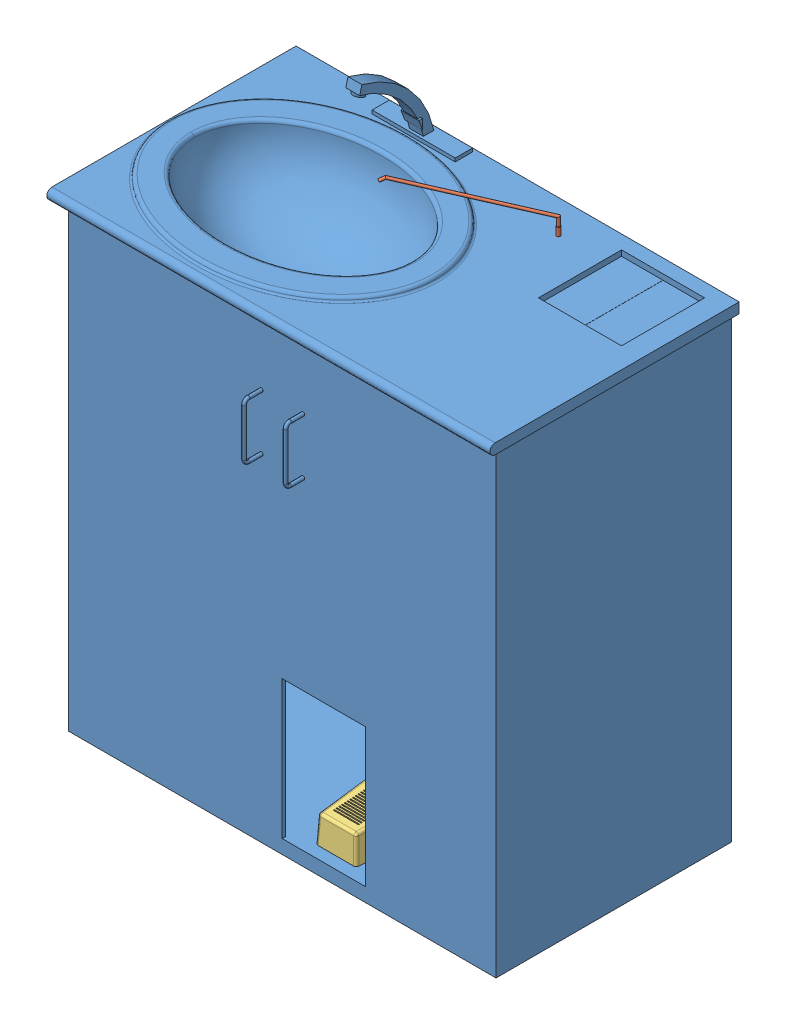
SolidWorks assembly Sink_Ass_Top_Garb, configuration Garbage Flaps. Lengths in mm.
Overall size (829.72 1010.12 517.52).
3 component instances, 3 part files, 2 mates.
Components (placement in the parent):
- Sink_new_top_cut-1: Sink_new_top_cut [Detailed] at origin
- Soap Pump Head-1: Soap Pump Head [Default] at (541.2492 865.124 -397.2986) x (0.707107 0 0.707107) z (-0.707107 0 0.707107) size (7 94.57 237.72)
- Soap Foot Pump-1: Soap Foot Pump [Default] at (445.731 25.4 -47.2721) size (89.29 56.68 113.79)
Mates (geometry in assembly coordinates):
- Coincident1: coincident anti-aligned: plane of Sink_new_top_cut-1 through (406.4 25.4 -431.8) normal (0 1 0); plane of Soap Foot Pump-1 through (445.731 25.4 -47.2721) normal (0 -1 0)
- Coincident2: coincident aligned: plane of Sink_new_top_cut-1 through (0 865.124 0) normal (0 1 0); plane of Soap Pump Head-1 through (541.2492 865.124 -397.2986) normal (0 1 0)
